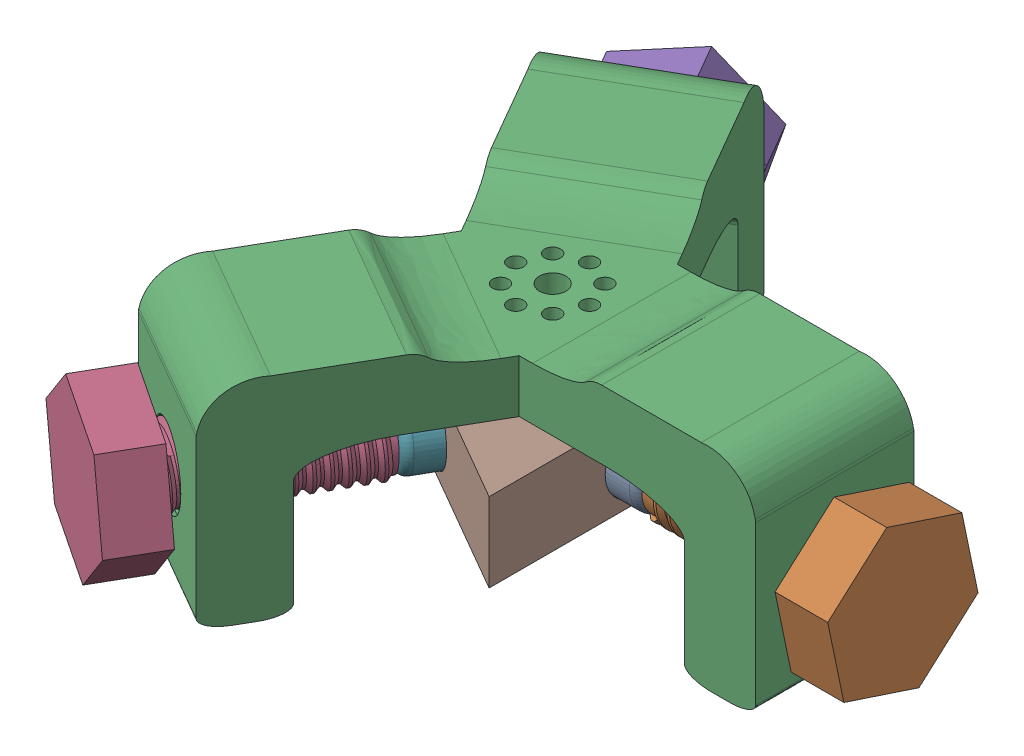
SolidWorks assembly demo, configuration 默认. Lengths in mm.
Overall size (116.7 42.9 133.26).
9 component instances, 4 part files, 16 mates.
Components (placement in the parent):
- newhead-1: newhead [默认] at (8.629 -20 0) x (0 -0.995568 -0.094045) z (0 -0.094045 0.995568) size (12.8 11.85 12.8)
- screw-1: screw [默认] at (66.4147 -20 0) x (0 0.665911 -0.746032) z (-1 0 0) size (30 25.98 43.55)
- clamp-1: clamp [默认] at (-10.6094 -68.125 -15) size (93.49 40.08 107.91)
- screw-2: screw [默认] at (-33.2074 -20 57.5169) x (0.588916 0.733192 0.340011) z (0.5 0 -0.866025) size (30 25.98 43.55)
- screw-3: screw [默认] at (-33.2074 -20 -57.5169) x (0.246885 0.958504 -0.142539) z (0.5 0 0.866025) size (30 25.98 43.55)
- newhead-2: newhead [默认] at (-4.3145 -20 -7.473) x (0.773856 0.44892 -0.446786) z (-0.388776 0.893572 0.22446) size (12.8 11.85 12.8)
- newhead-3: newhead [默认] at (-4.3145 -20 7.473) x (0.47026 -0.839727 0.271505) z (-0.727225 -0.543009 -0.419863) size (12.8 11.85 12.8)
- holder-1: holder [默认] at (-8.2324 -27.5 0) x (0 0 -1) z (0 1 0) size (57.04 49.39 15)
- EnclosureAssy_IM_Final.STEP-1: EnclosureAssy_IM_Final.STEP [默认] at (-4.6694 -47.85 0) x (0 0 -1) z (0 1 0) (suppressed, hidden)
Mates (geometry in assembly coordinates):
- 同心1: concentric: sphere of newhead-1; sphere of screw-1
- 同心2: concentric aligned: cylinder of newhead-1 through (8.629 -20 0) axis (-1 0 0) radius 2.4; cylinder of screw-1 through (25.4147 -20 0) axis (-1 0 0) radius 2.55
- 重合1: coincident: point of clamp-1; point of assembly
- 同心3: concentric anti-aligned: circle of newhead-1; circle of clamp-1
- 同心4: concentric: sphere of screw-2; sphere of newhead-3
- 同心5: concentric aligned: cylinder of screw-2 through (-12.7074 -20 22.0098) axis (0.5 0 -0.866025) radius 2.55; cylinder of newhead-3 through (-4.3145 -20 7.473) axis (0.5 0 -0.866025) radius 2.4
- 同心7: concentric anti-aligned: circle of clamp-1; circle of newhead-3
- 同心8: concentric: sphere of screw-3; sphere of newhead-2
- 同心9: concentric aligned: cylinder of screw-3 through (-12.7074 -20 -22.0098) axis (0.5 0 0.866025) radius 2.55; cylinder of newhead-2 through (-4.3145 -20 -7.473) axis (0.5 0 0.866025) radius 2.4
- 同心10: concentric anti-aligned: circle of clamp-1; circle of newhead-2
- 平行1: parallel anti-aligned: plane of clamp-1 through (-32.9904 -10 27.141) normal (0 -1 0); plane of holder-1 through (-8.2324 -12.5 0) normal (0 1 0)
- 同心11: concentric anti-aligned: cylinder of newhead-3 through (-4.3145 -20 7.473) axis (0.5 0 -0.866025) radius 6.4; cylinder of holder-1 through (-7.9824 -20 13.8259) axis (-0.5 0 0.866025) radius 6.5
- 同心12: concentric anti-aligned: cylinder of newhead-1 through (8.629 -20 0) axis (-1 0 0) radius 6.4; cylinder of holder-1 through (15.9647 -20 0) axis (1 0 0) radius 6.5
- 重合5: coincident anti-aligned: plane of newhead-1 through (15.9647 -20 0) normal (-1 0 0); plane of holder-1 through (15.9647 -20 0) normal (1 0 0)
- 重合6: coincident anti-aligned: plane of newhead-3 through (-7.9824 -20 13.8259) normal (0.5 0 -0.866025); plane of holder-1 through (-7.9824 -20 13.8259) normal (-0.5 0 0.866025)
- 重合7: coincident anti-aligned: plane of newhead-2 through (-7.9824 -20 -13.8259) normal (0.5 0 0.866025); plane of holder-1 through (-7.9824 -20 -13.8259) normal (-0.5 0 -0.866025)
